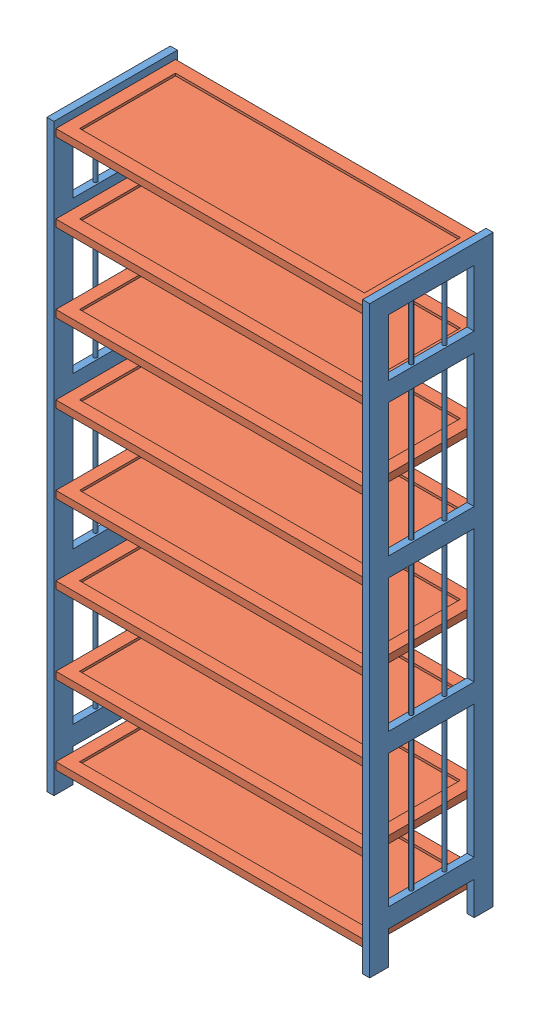
SolidWorks assembly 鞋柜, configuration 默认. Lengths in mm.
Overall size (680 1230 260).
10 component instances, 2 part files, 9 mates.
Components (placement in the parent):
- 鞋柜-侧板-1: 鞋柜-侧板 [默认] at (340 0 0) size (15 1230 260)
- 鞋柜-侧板-2: 鞋柜-侧板 [默认] at (-325 0 0) size (15 1230 260)
- 鞋柜-横板-1: 鞋柜-横板 [默认] at (0 1207.5 0) size (650 15 252)
- 鞋柜-横板-2: 鞋柜-横板 [默认] at (0 1042.5 0) size (650 15 252)
- 鞋柜-横板-3: 鞋柜-横板 [默认] at (0 877.5 0) size (650 15 252)
- 鞋柜-横板-4: 鞋柜-横板 [默认] at (0 712.5 0) size (650 15 252)
- 鞋柜-横板-5: 鞋柜-横板 [默认] at (0 547.5 0) size (650 15 252)
- 鞋柜-横板-6: 鞋柜-横板 [默认] at (0 382.5 0) size (650 15 252)
- 鞋柜-横板-7: 鞋柜-横板 [默认] at (0 217.5 0) size (650 15 252)
- 鞋柜-横板-8: 鞋柜-横板 [默认] at (0 52.5 0) size (650 15 252)
Mates (geometry in assembly coordinates):
- 重合4: coincident aligned: plane of 鞋柜-侧板-1 through (340 0 0) normal (0 0 1); plane of assembly through (0 0 0) normal (0 0 1)
- 重合5: coincident aligned: plane of 鞋柜-侧板-1 through (340 0 0) normal (0 1 0); plane of assembly through (0 0 0) normal (0 1 0)
- 距离4: distance = 340 mm aligned: plane of 鞋柜-侧板-1 through (340 0 0) normal (1 0 0); plane of assembly through (0 0 0) normal (1 0 0)
- 重合1: coincident aligned: plane of 鞋柜-侧板-1 through (340 0 0) normal (0 0 1); plane of 鞋柜-侧板-2 through (-325 0 0) normal (0 0 1)
- 重合2: coincident aligned: plane of 鞋柜-侧板-1 through (340 0 0) normal (0 1 0); plane of 鞋柜-侧板-2 through (-325 0 0) normal (0 1 0)
- 距离1: distance = 680 mm anti-aligned: plane of 鞋柜-侧板-1 through (340 0 0) normal (1 0 0); plane of 鞋柜-侧板-2 through (-340 0 0) normal (-1 0 0)
- 重合9: coincident aligned: plane of 鞋柜-横板-1 through (0 82.5 0) normal (0 0 1); plane of assembly through (0 0 0) normal (0 0 1)
- 重合10: coincident aligned: plane of 鞋柜-横板-1 through (0 82.5 0) normal (1 0 0); plane of assembly through (0 0 0) normal (1 0 0)
- 距离6: distance = 15 mm aligned: plane of 鞋柜-侧板-1 through (325 1230 130) normal (0 1 0); plane of 鞋柜-横板-1 through (0 1215 0) normal (0 1 0)
